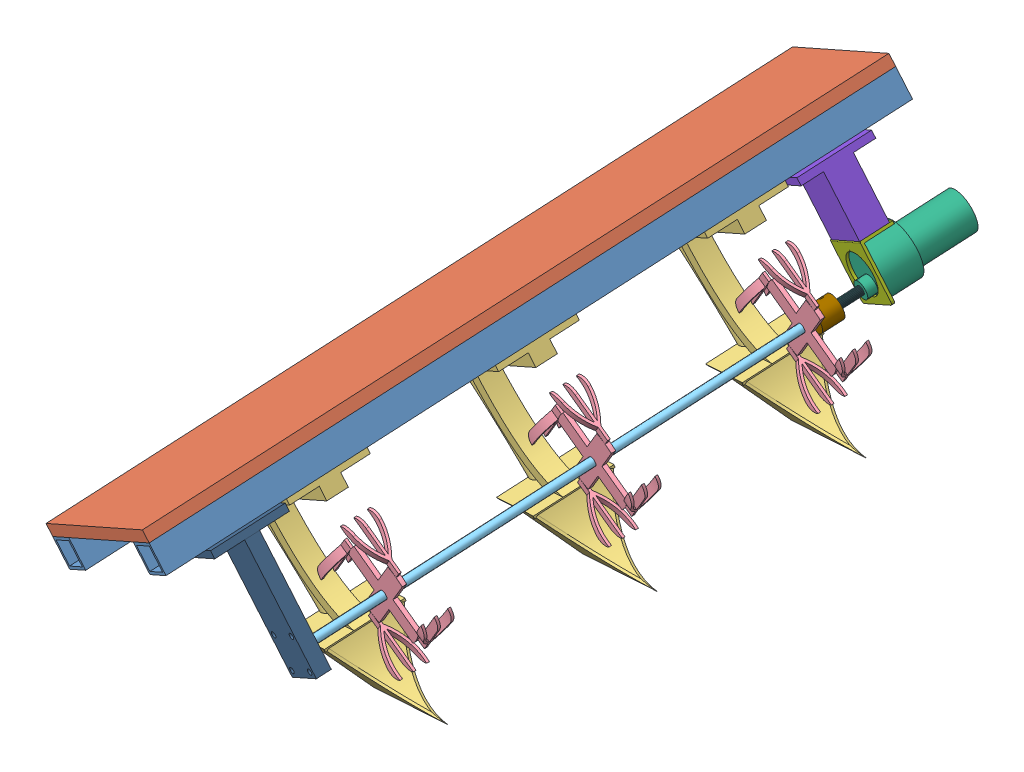
SolidWorks assembly seed drill assem, configuration Default. Lengths in mm.
Overall size (273.6 286.78 514.45).
16 component instances, 10 part files, 31 mates.
Components (placement in the parent):
- aluminium channel-1: aluminium channel [Default] at (415.7959 224.0805 380.8246) x (-0.834117 -0.4994 -0.234196) z (0.147807 0.20669 -0.967178) size (20 20 500)
- wood frame-1: wood frame [Default] at (405.7276 259.1966 128.3063) x (0.147807 0.20669 -0.967178) z (-0.531414 0.841355 0.098589) size (500 120 8)
- aluminium channel-2: aluminium channel [Default] at (332.3842 174.1405 357.405) x (-0.834117 -0.4994 -0.234196) z (0.147807 0.20669 -0.967178) size (20 20 500)
- seed drill part 1-1: seed drill part 1 [Default] at (450.4532 160.726 -9.8469) x (0.147807 0.20669 -0.967178) z (0.949603 0.243659 0.197192) size (58.11 156.15 137.2)
- seed drill part 1-2: seed drill part 1 [Default] at (429.7603 131.7894 125.558) x (0.147807 0.20669 -0.967178) z (0.949603 0.243659 0.197192) size (58.11 156.15 137.2)
- seed drill part 1-3: seed drill part 1 [Default] at (409.0673 102.8528 260.9628) x (0.147807 0.20669 -0.967178) z (0.949603 0.243659 0.197192) size (58.11 156.15 137.2)
- Assem1-1: Assem1 [Default] at (417.1093 69.4656 752.1727) x (-0.358314 -0.900292 -0.247155) z (0.921826 -0.383085 0.059009) size (94.45 400 94.45)
  - chup-1: chup [Default] at (3.5191 639.4228 -13.585) x (0.97133 0 -0.237735) z (0.237735 0 0.97133) size (78.12 22.31 78.12)
  - chup-2: chup [Default] at (3.5191 779.4228 -13.585) x (-0.97133 0 0.237735) z (-0.237735 0 -0.97133) size (78.12 22.31 78.12)
  - chup-3: chup [Default] at (3.5191 499.4228 -13.585) x (-0.97133 0 0.237735) z (-0.237735 0 -0.97133) size (78.12 22.31 78.12)
  - shaft-2: shaft [Default] at (3.5191 440.9228 -13.585) size (6 400 6)
- DC motor-1: DC motor [Default] at (521.6824 248.101 -47.6226) x (0.834117 0.4994 0.234196) z (0.147807 0.20669 -0.967178) size (37 37 101.8)
- DCclamp-1: DCclamp [Default] at (527.2824 272.905 -41.466) x (0.147807 0.20669 -0.967178) z (-0.834117 -0.4994 -0.234196) size (22.5 39 37)
- motor block-1: motor block [Default] at (512.805 267.5017 -53.1047) x (0.834117 0.4994 0.234196) z (-0.147807 -0.20669 0.967178) size (35 47.8 50)
- shaft1-1: shaft1 [Default] at (519.6674 234.1919 -10.7862) x (-0.531414 0.841355 0.098589) z (-0.834117 -0.4994 -0.234196) size (16.38 15 16.38)
- ball bearing happy seeder-1: ball bearing happy seeder [Default] at (468.0533 162.0158 326.9522) x (-0.834117 -0.4994 -0.234196) z (0.531414 -0.841355 -0.098589) size (30.02 50 90)
Mates (geometry in assembly coordinates):
- Coincident1: coincident: plane of aluminium channel-1 through (492.7264 340.833 -99.4363) normal (-0.531414 0.841355 0.098589); plane of wood frame-1 through (405.7276 259.1966 128.3063) normal (0.531414 -0.841355 -0.098589)
- Coincident3: coincident: line of wood frame-1 through (492.7264 340.833 -99.4363) axis (-0.834117 -0.4994 -0.234196); line of aluminium channel-1 through (476.044 330.845 -104.1203) axis (0.834117 0.4994 0.234196)
- Coincident5: coincident: line of aluminium channel-1 through (492.7264 340.833 -99.4363) axis (-0.147807 -0.20669 0.967178); line of wood frame-1 through (418.823 237.4881 384.1524) axis (0.147807 0.20669 -0.967178)
- Coincident6: coincident: plane of wood frame-1 through (405.7276 259.1966 128.3063) normal (0.531414 -0.841355 -0.098589); plane of aluminium channel-2 through (409.3146 290.8931 -122.8559) normal (-0.531414 0.841355 0.098589)
- Coincident7: coincident: line of wood frame-1 through (492.7264 340.833 -99.4363) axis (-0.834117 -0.4994 -0.234196); line of aluminium channel-2 through (392.6323 280.9051 -127.5399) axis (0.834117 0.4994 0.234196)
- Coincident8: coincident: line of wood frame-1 through (392.6323 280.9051 -127.5399) axis (-0.147807 -0.20669 0.967178); line of aluminium channel-2 through (392.6323 280.9051 -127.5399) axis (-0.147807 -0.20669 0.967178)
- Coincident13: coincident: plane of aluminium channel-2 through (419.9429 274.0659 -124.8277) normal (0.531414 -0.841355 -0.098589); plane of seed drill part 1-1 through (435.9846 269.8179 -2.1067) normal (-0.531414 0.841355 0.098589)
- Width3: width: plane of seed drill part 1-1 through (490.8078 287.6463 -4.8071) normal (0.834117 0.4994 0.234196); plane of seed drill part 1-1 through (400.7231 233.7111 -30.1003) normal (-0.834117 -0.4994 -0.234196); plane of aluminium channel-1 through (503.3547 324.0059 -101.4081) normal (0.834117 0.4994 0.234196); plane of aluminium channel-2 through (403.2606 264.0779 -129.5116) normal (-0.834117 -0.4994 -0.234196)
- Coincident19: coincident: plane of aluminium channel-1 through (503.3547 324.0059 -101.4081) normal (0.531414 -0.841355 -0.098589); plane of seed drill part 1-2 through (415.2917 240.8813 133.2982) normal (-0.531414 0.841355 0.098589)
- Width5: width: plane of seed drill part 1-2 through (470.1148 258.7097 130.5977) normal (0.834117 0.4994 0.234196); plane of seed drill part 1-2 through (380.0301 204.7745 105.3046) normal (-0.834117 -0.4994 -0.234196); plane of aluminium channel-2 through (403.2606 264.0779 -129.5116) normal (-0.834117 -0.4994 -0.234196); plane of aluminium channel-1 through (503.3547 324.0059 -101.4081) normal (0.834117 0.4994 0.234196)
- Coincident20: coincident: line of aluminium channel-1 through (466.403 272.3334 140.3863) axis (-0.834117 -0.4994 -0.234196); moEndPointRef_w of seed drill part 1-2
- Coincident21: coincident: plane of aluminium channel-1 through (503.3547 324.0059 -101.4081) normal (0.531414 -0.841355 -0.098589); plane of seed drill part 1-3 through (394.5988 211.9447 268.703) normal (-0.531414 0.841355 0.098589)
- Width6: width: plane of seed drill part 1-3 through (449.4219 229.7731 266.0026) normal (0.834117 0.4994 0.234196); plane of seed drill part 1-3 through (359.3372 175.8379 240.7094) normal (-0.834117 -0.4994 -0.234196); plane of aluminium channel-2 through (403.2606 264.0779 -129.5116) normal (-0.834117 -0.4994 -0.234196); plane of aluminium channel-1 through (503.3547 324.0059 -101.4081) normal (0.834117 0.4994 0.234196)
- Coincident22: coincident: line of aluminium channel-1 through (445.71 243.3968 275.7911) axis (-0.834117 -0.4994 -0.234196); moEndPointRef_w of seed drill part 1-3
- Coincident23: coincident: line of aluminium channel-2 through (403.6842 251.33 -18.4382) axis (-0.834117 -0.4994 -0.234196); moEndPointRef_w of seed drill part 1-1
- Width8: width: plane of Assem1-1/chup-1 through (498.2798 204.2839 129.1644) normal (0.147807 0.20669 -0.967178); plane of Assem1-1/chup-1 through (497.8364 203.6638 132.0659) normal (-0.147807 -0.20669 0.967178); plane of seed drill part 1-2 through (422.9441 228.7658 131.8785) normal (-0.147807 -0.20669 0.967178); plane of seed drill part 1-2 through (425.0725 231.7421 117.9511) normal (0.147807 0.20669 -0.967178)
- Concentric3: concentric: circle of DC motor-1; circle of DCclamp-1
- Parallel2: parallel: plane of aluminium channel-1 through (503.3547 324.0059 -101.4081) normal (0.531414 -0.841355 -0.098589); plane of DCclamp-1 through (495.2094 255.9032 -48.9669) normal (-0.531414 0.841355 0.098589)
- Coincident37: coincident: plane of DCclamp-1 through (495.2094 255.9032 -48.9669) normal (-0.531414 0.841355 0.098589); plane of motor block-1 through (512.805 267.5017 -53.1047) normal (0.531414 -0.841355 -0.098589)
- Coincident38: coincident: plane of DCclamp-1 through (526.6032 273.5396 -40.4003) normal (0.834117 0.4994 0.234196); plane of motor block-1 through (503.4785 318.5249 -53.9655) normal (0.834117 0.4994 0.234196)
- Coincident39: coincident: plane of DCclamp-1 through (515.7868 222.8836 -51.8447) normal (-0.147807 -0.20669 0.967178); plane of motor block-1 through (471.3283 296.9121 -42.8188) normal (-0.147807 -0.20669 0.967178)
- Concentric5: concentric: cylinder of DC motor-1 through (517.1599 242.569 -19.7186) axis (0.531414 -0.841355 -0.098589) radius 1.3505; cylinder of shaft1-1 through (515.8313 244.6724 -19.4721) axis (0.531414 -0.841355 -0.098589) radius 1.5
- Coincident41: coincident: plane of wood frame-1 through (488.475 347.5639 -98.6476) normal (0.147807 0.20669 -0.967178); plane of DC motor-1 through (531.2899 261.5358 -110.4891) normal (0.147807 0.20669 -0.967178)
- Coincident42: coincident: plane of DC motor-1 through (521.6824 248.101 -47.6226) normal (-0.147807 -0.20669 0.967178); plane of DCclamp-1 through (496.4201 254.4272 -50.1313) normal (0.147807 0.20669 -0.967178)
- Concentric7: concentric: cylinder of Assem1-1/shaft-2 through (527.6194 245.3119 -62.8204) axis (-0.147807 -0.20669 0.967178) radius 3; cylinder of DC motor-1 through (519.963 234.6053 -12.7206) axis (0.147807 0.20669 -0.967178) radius 3
- Concentric8: concentric: cylinder of DC motor-1 through (519.963 234.6053 -12.7206) axis (0.147807 0.20669 -0.967178) radius 3; cylinder of shaft1-1 through (521.8845 237.2923 -25.2939) axis (-0.147807 -0.20669 0.967178) radius 8.189
- Coincident45: coincident: plane of aluminium channel-1 through (503.3547 324.0059 -101.4081) normal (0.531414 -0.841355 -0.098589); plane of motor block-1 through (487.4034 307.7185 -48.3922) normal (-0.531414 0.841355 0.098589)
- Concentric9: concentric: cylinder of Assem1-1/shaft-2 through (527.6194 245.3119 -62.8204) axis (-0.147807 -0.20669 0.967178) radius 3; cylinder of ball bearing happy seeder-1 through (468.4967 162.6359 324.0507) axis (0.147807 0.20669 -0.967178) radius 4
- Coincident46: coincident: plane of Assem1-1/shaft-2 through (468.4967 162.6359 324.0507) normal (-0.147807 -0.20669 0.967178); plane of ball bearing happy seeder-1 through (468.4967 162.6359 324.0507) normal (0.147807 0.20669 -0.967178)
- Parallel3: parallel: plane of aluminium channel-1 through (503.3547 324.0059 -101.4081) normal (0.531414 -0.841355 -0.098589); plane of ball bearing happy seeder-1 through (428.1972 225.1175 334.3464) normal (-0.531414 0.841355 0.098589)
- Distance1: distance = 5 mm: plane of aluminium channel-1 through (503.3547 324.0059 -101.4081) normal (0.834117 0.4994 0.234196); plane of ball bearing happy seeder-1 through (440.4291 224.2794 356.7153) normal (0.834117 0.4994 0.234196)
